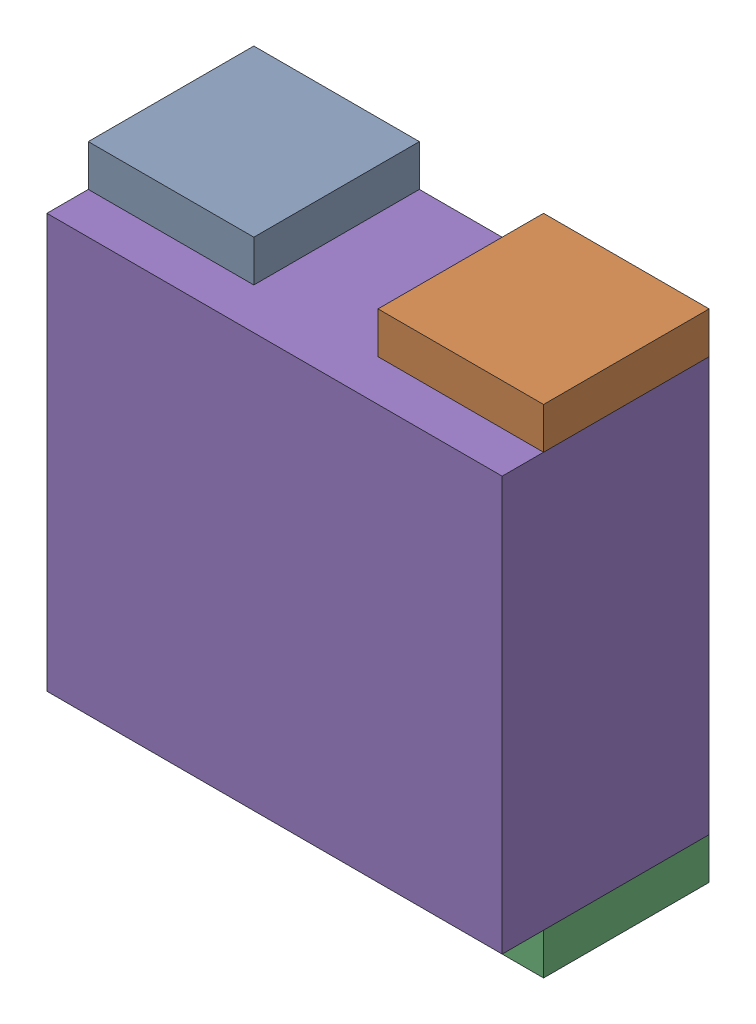
SolidWorks assembly RN17, configuration Default. Lengths in mm.
Overall size (1.1 1.2 0.5).
10 component instances, 2 part files, 0 mates.
Components (placement in the parent):
- 810157616-1: 810157616 [Default] at (132.65 66.5 0) size (0.4 0.1 0.4)
  - Extruded_12-1: Extruded_12 [Default] at origin size (0.4 0.1 0.4)
- 810157616-2: 810157616 [Default] at (133.35 66.5 0) size (0.4 0.1 0.4)
  - Extruded_12-1: Extruded_12 [Default] at origin size (0.4 0.1 0.4)
- 810157616-3: 810157616 [Default] at (133.35 65.4 0) size (0.4 0.1 0.4)
  - Extruded_12-1: Extruded_12 [Default] at origin size (0.4 0.1 0.4)
- 810157616-4: 810157616 [Default] at (132.65 65.4 0) size (0.4 0.1 0.4)
  - Extruded_12-1: Extruded_12 [Default] at origin size (0.4 0.1 0.4)
- 810156720-1: 810156720 [Default] at (133 65.95 0) size (1.1 1 0.5)
  - Extruded_13-1: Extruded_13 [Default] at origin size (1.1 1 0.5)
